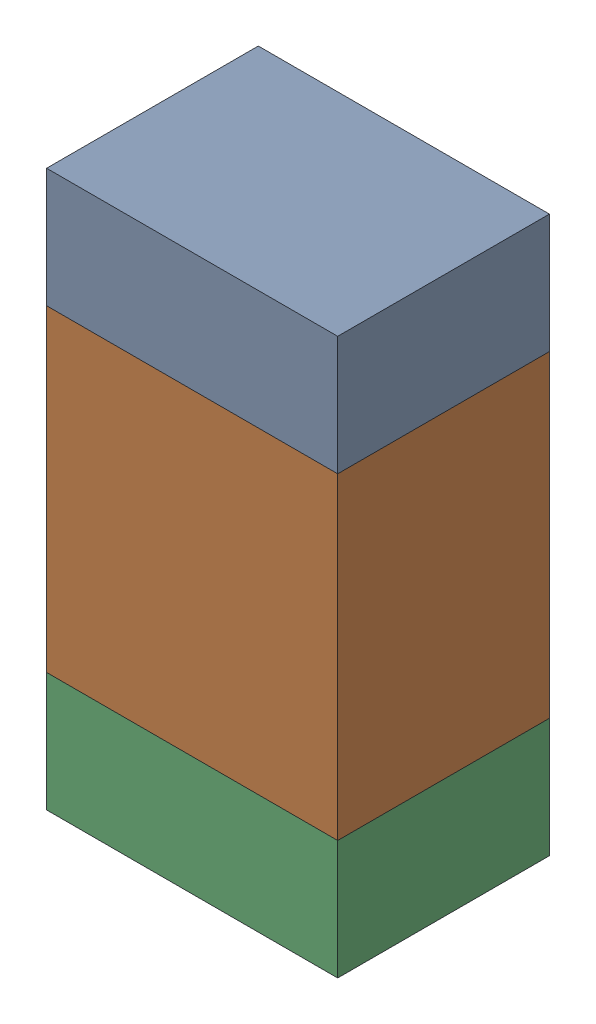
SolidWorks assembly R600_2PCB, configuration Default. Lengths in mm.
Overall size (0.55 1.05 0.4).
6 component instances, 2 part files, 0 mates.
Components (placement in the parent):
- 846483288-1: 846483288 [Default] at (104.7999 105.0124 -2.0638) size (0.55 0.22 0.4)
  - Extruded_12-1: Extruded_12 [Default] at origin size (0.55 0.22 0.4)
- 846483424-1: 846483424 [Default] at (104.7999 104.5999 -2.0638) size (0.55 0.6 0.4)
  - Extruded_13-1: Extruded_13 [Default] at origin size (0.55 0.6 0.4)
- 846483288-2: 846483288 [Default] at (104.7999 104.1874 -2.0638) size (0.55 0.22 0.4)
  - Extruded_12-1: Extruded_12 [Default] at origin size (0.55 0.22 0.4)
